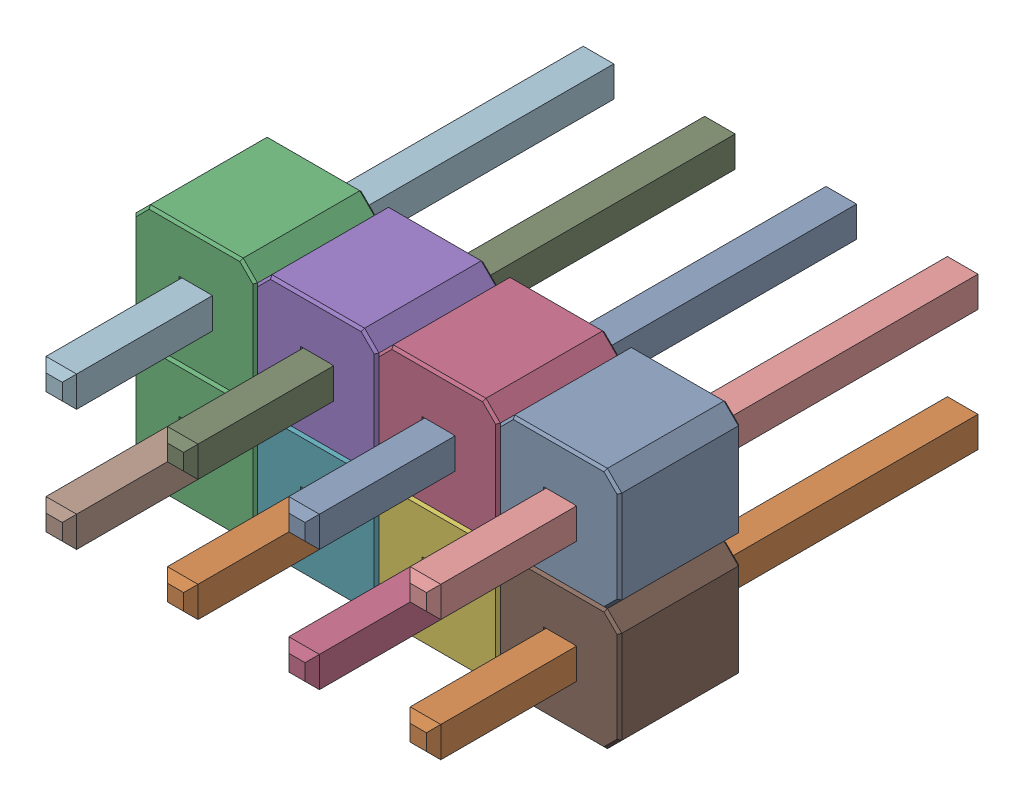
SolidWorks assembly X1_XLR1, configuration Default. Lengths in mm.
Overall size (10.16 5.08 11.54).
17 component instances, 2 part files, 0 mates.
Components (placement in the parent):
- PLD-8-1: PLD-8 [Default] at (143.6251 88.0109 -1.2114) x (1 0 0) z (0 0 -1) size (10.16 5.08 11.54)
  - _______________________-1: _______________________ [Default] at (-2.54 0 -3) size (0.64 0.64 11.54)
  - _______________________-2: _______________________ [Default] at (-5.08 2.54 -3) size (0.64 0.64 11.54)
  - _________-1: _________ [Default] at (-7.6724 2.5342 -0.0112) size (2.54 2.54 2.54)
  - _______________________-3: _______________________ [Default] at (-2.54 2.54 -3) size (0.64 0.64 11.54)
  - _________-2: _________ [Default] at (-5.1324 -0.0058 -0.0112) size (2.54 2.54 2.54)
  - _________-3: _________ [Default] at (-2.5924 2.5342 -0.0112) size (2.54 2.54 2.54)
  - _________-4: _________ [Default] at (-5.1324 2.5342 -0.0112) size (2.54 2.54 2.54)
  - _______________________-4: _______________________ [Default] at (-7.62 2.54 -3) size (0.64 0.64 11.54)
  - _______________________-5: _______________________ [Default] at (-5.08 0 -3) size (0.64 0.64 11.54)
  - _______________________-6: _______________________ [Default] at (0 0 -3) size (0.64 0.64 11.54)
  - _________-5: _________ [Default] at (-0.0524 2.5342 -0.0112) size (2.54 2.54 2.54)
  - _______________________-7: _______________________ [Default] at (-7.62 0 -3) size (0.64 0.64 11.54)
  - _________-6: _________ [Default] at (-0.0524 -0.0058 -0.0112) size (2.54 2.54 2.54)
  - _______________________-8: _______________________ [Default] at (0 2.54 -3) size (0.64 0.64 11.54)
  - _________-7: _________ [Default] at (-7.6724 -0.0058 -0.0112) size (2.54 2.54 2.54)
  - _________-8: _________ [Default] at (-2.5924 -0.0058 -0.0112) size (2.54 2.54 2.54)
